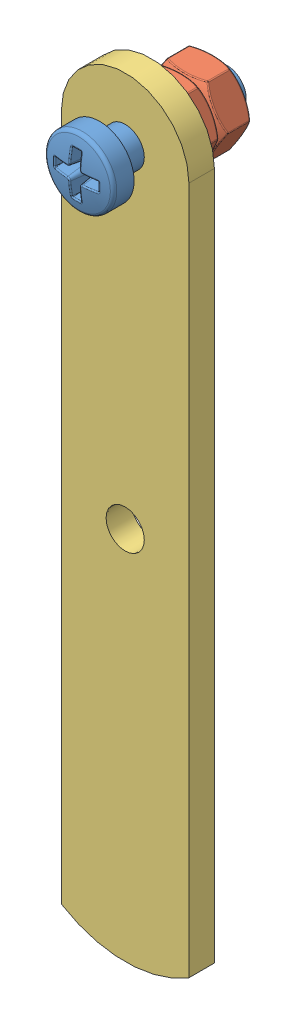
SolidWorks assembly Walking_robot_(assembled_front_legs), configuration Default. Lengths in mm.
Overall size (10 60.4 11.98).
4 component instances, 3 part files, 0 mates.
Components (placement in the parent):
- Walking_robot_(bolt_3x10)-1: Walking_robot_(bolt_3x10) [Default] at (-88.5069 37.6493 37.7132) x (0 0 1) z (-1 0 0) size (11.98 5.4 5.4)
- Walking_robot_(nut_3)-1: Walking_robot_(nut_3) [Default] at (-88.5069 37.6493 31.2132) size (6.75 5.87 2.78)
- Walking_robot_(nut_3)-2: Walking_robot_(nut_3) [Default] at (-88.5069 37.6493 28.7132) size (6.75 5.87 2.78)
- analysisWalking_robot_(legs)-1: analysisWalking_robot_(legs) [Default] at (-88.5069 13.1493 33.7132) size (10 60.4 2)
